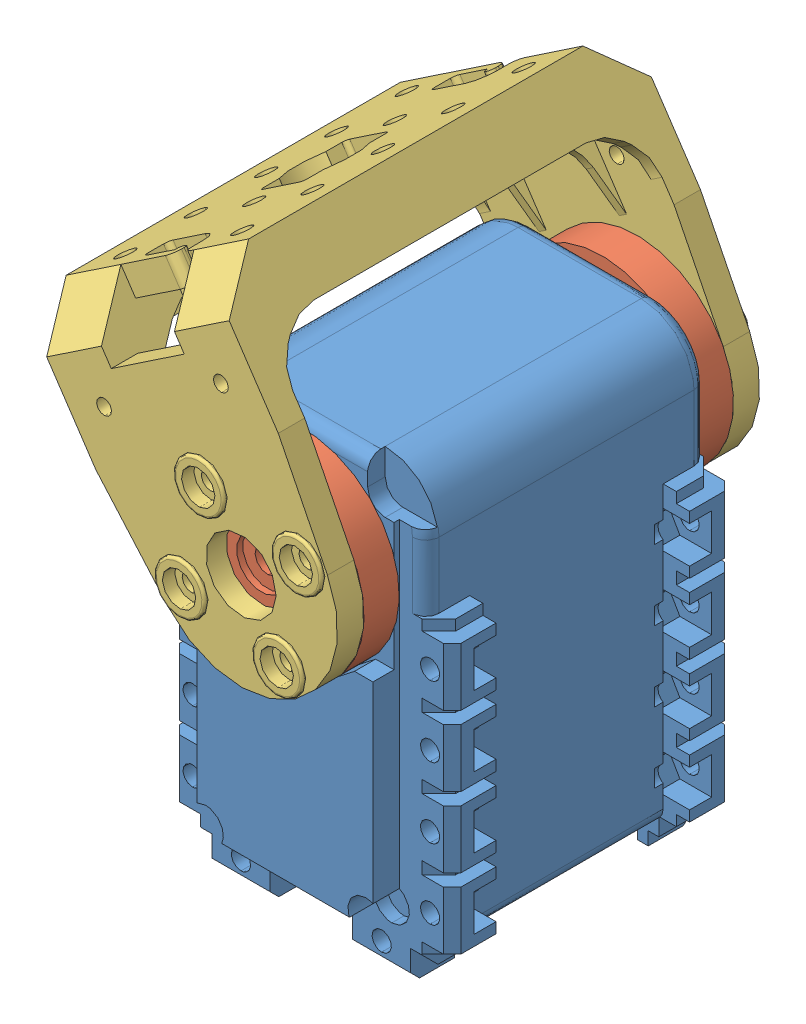
SolidWorks assembly montage_bras_servo_essai, configuration Default. Lengths in mm.
Overall size (41.39 67.05 48.81).
4 component instances, 3 part files, 8 mates.
Components (placement in the parent):
- AX-12_modif-1: AX-12_modif [Défaut] at (-2.6768 21.8769 -4.3025) size (32 50.06 38.01)
- attache_ax-12-1: attache_ax-12 [Default] at (-2.6768 21.8769 12.6975) x (-0.829959 -0.557825 0) z (0 0 1) size (22 22 4.7)
- F2-1: F2 [Défaut] at (-2.6768 21.8769 -4.3025) x (0 0 -1) z (-0.557825 0.829959 0) size (48.81 25 37)
- attache_ax-12-2: attache_ax-12 [Default] at (-2.6768 21.8769 -21.3025) x (-0.557825 0.829959 0) z (0 0 -1) size (22 22 4.7)
Mates (geometry in assembly coordinates):
- Coïncidente1: coincident anti-aligned: plane of AX-12_modif-1 through (8.7632 10.4369 12.6975) normal (0 0 1); plane of attache_ax-12-1 through (-2.6768 21.8769 12.6975) normal (0 0 -1)
- Tangent6: tangent: face of AX-12_modif-1; cylinder of attache_ax-12-1
- Coïncidente2: coincident anti-aligned: plane of attache_ax-12-1 through (-2.6768 21.8769 16.6975) normal (0 0 1); plane of F2-1 through (-2.6768 21.8769 16.6975) normal (0 0 -1)
- Coaxiale1: concentric anti-aligned: cylinder of attache_ax-12-1; cylinder of F2-1
- Coïncidente4: coincident anti-aligned: plane of F2-1 through (-2.6768 21.8769 -25.3025) normal (0 0 1); plane of attache_ax-12-2 through (-2.6768 21.8769 -25.3025) normal (0 0 -1)
- Coaxiale4: concentric anti-aligned: cylinder of F2-1; cylinder of attache_ax-12-2
- Coaxiale5: concentric aligned: cylinder of F2-1; cylinder of attache_ax-12-2
- Coaxiale6: concentric anti-aligned: cylinder of attache_ax-12-1; cylinder of F2-1
